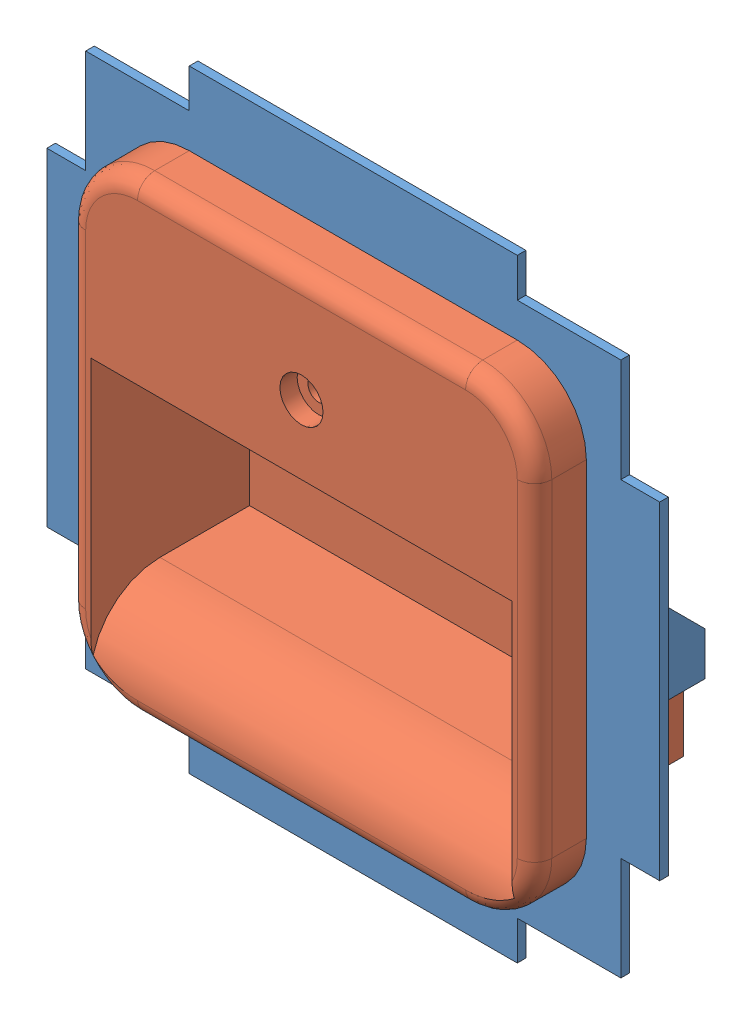
SolidWorks assembly Keystone-Unterputzeinsatz, configuration 2er. Lengths in mm.
Overall size (71 71 21.25).
2 component instances, 2 part files, 6 mates.
Components (placement in the parent):
- Keystone-Montageplatte-1: Keystone-Montageplatte [2er] at (-35.5 -35.5 -6) x (-1 0 0) z (0 0 -1) size (71 71 14.87)
- Keystone-Frontplatte-1: Keystone-Frontplatte [2er] at (-35.5 -35.5 0) size (54 54 19.77)
Mates (geometry in assembly coordinates):
- Deckungsgleich1: coincident anti-aligned: plane of Keystone-Montageplatte-1 through (-35.5 -35.5 -6) normal (0 0 1); plane of Keystone-Frontplatte-1 through (-54.5 -54.5 -6) normal (0 0 -1)
- Konzentrisch1: concentric aligned: cylinder of Keystone-Montageplatte-1 through (-35.5 -21 -7) axis (0 0 1) radius 1.25; cylinder of Keystone-Frontplatte-1 through (-35.5 -21 -10) axis (0 0 1) radius 1.25
- Parallel1: parallel aligned: plane of Keystone-Montageplatte-1 through (-16.5 -71 -7) normal (0 -1 0); plane of Keystone-Frontplatte-1 through (-54.5 -62.5 -6) normal (0 -1 0)
- Deckungsgleich2: coincident aligned: plane of Keystone-Frontplatte-1 through (-54.5 -54.5 0) normal (0 0 1); plane of assembly through (0 0 0) normal (0 0 1)
- Deckungsgleich3: coincident aligned: plane of Keystone-Montageplatte-1 through (0 -16.5 -7) normal (1 0 0); plane of assembly through (0 0 0) normal (1 0 0)
- Deckungsgleich4: coincident aligned: plane of Keystone-Montageplatte-1 through (-54.5 0 -7) normal (0 1 0); plane of assembly through (0 0 0) normal (0 1 0)
